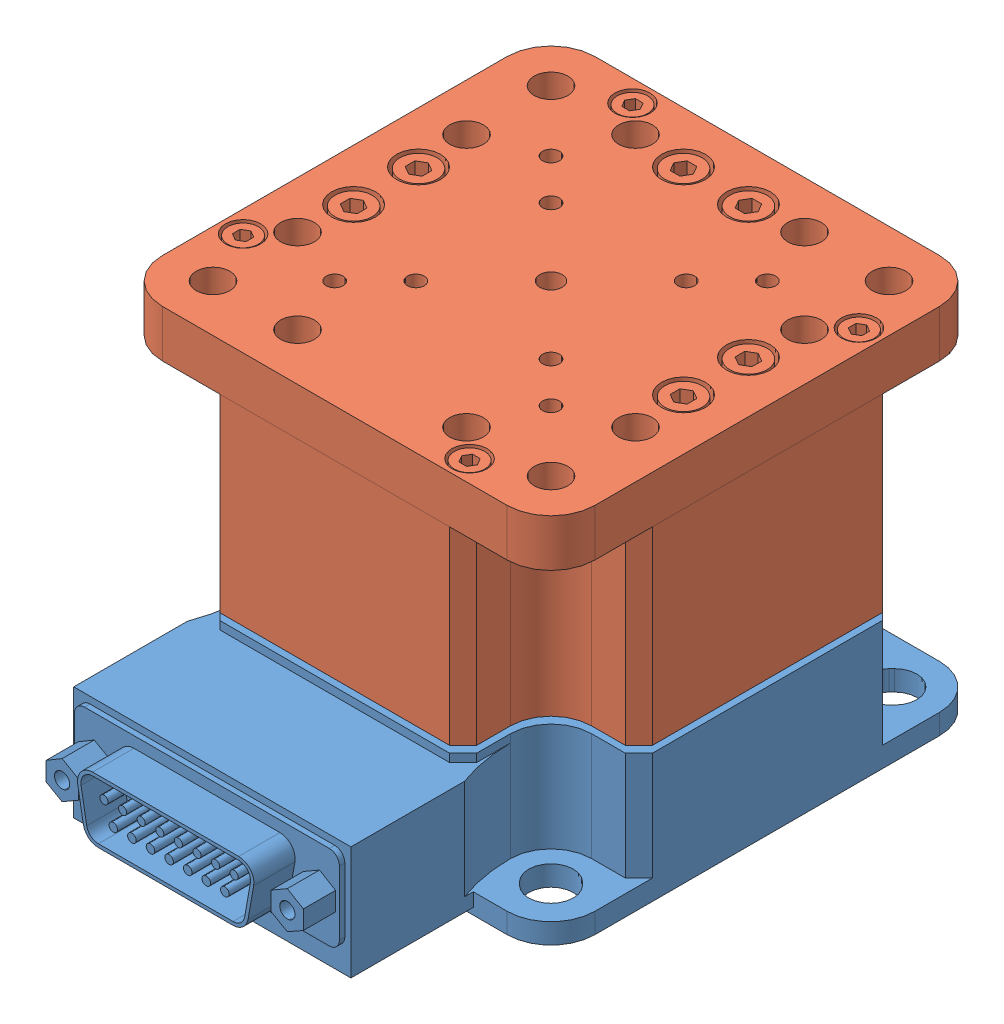
SolidWorks assembly VSR, configuration VSR20x-T3A. Lengths in mm.
Overall size (64 55 89).
2 component instances, 2 part files, 3 mates.
Components (placement in the parent):
- VSR_base^VSR-1: VSR_base^VSR [VSR20-T3A] at origin size (64 48 89) (virtual)
- VSR_top^VSR-1: VSR_top^VSR [VSR20] at origin size (64 35 64) (virtual)
Mates (geometry in assembly coordinates):
- Coincident1: coincident aligned: plane of VSR_top^VSR-1 through (0 0 0) normal (0 0 1); plane of assembly through (0 0 0) normal (0 0 1)
- Coincident2: coincident aligned: plane of VSR_top^VSR-1 through (0 0 0) normal (1 0 0); plane of assembly through (0 0 0) normal (1 0 0)
- LimitDistance1: limit distance = 0 mm aligned: plane of VSR_top^VSR-1 through (0 0 0) normal (0 1 0); plane of assembly through (0 0 0) normal (0 1 0)
